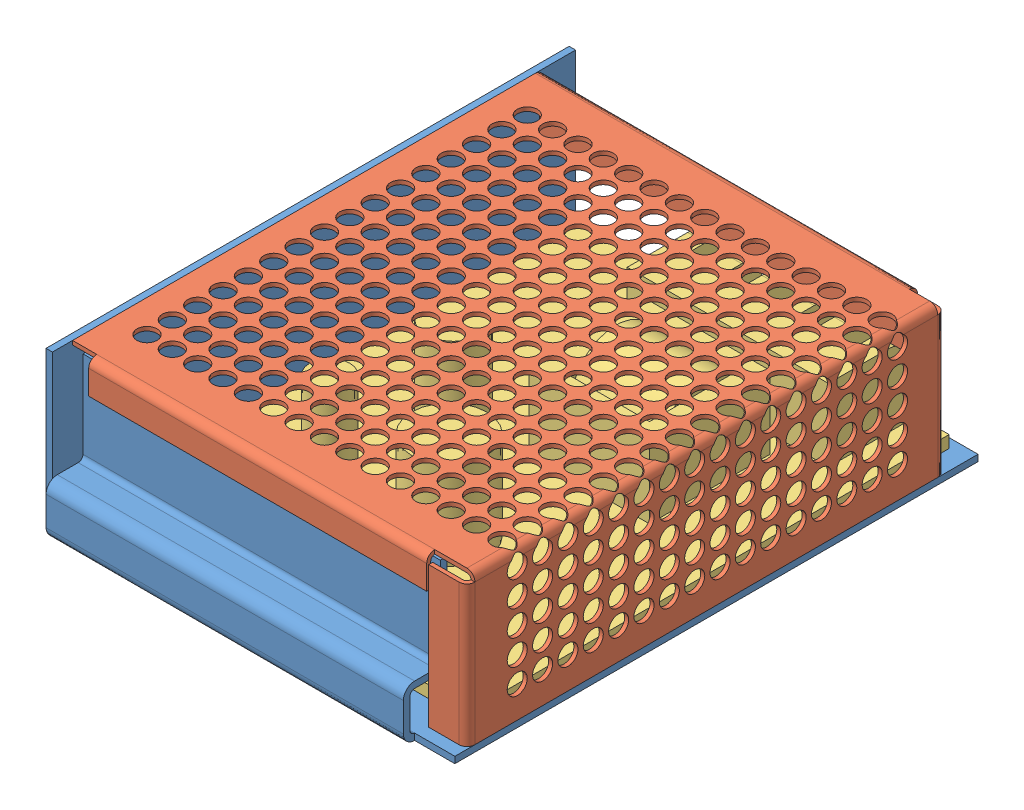
SolidWorks assembly SMPS-24v, configuration Default. Lengths in mm.
Overall size (101.6 38.6 132.8).
8 component instances, 4 part files, 0 mates.
Components (placement in the parent):
- Smps part 1-edit-00-1: Smps part 1-edit-00 [Default] at (3.0479 73.0195 107.4159) size (101.6 38.6 132.8)
- Smps part 2-edit-00-1: Smps part 2-edit-00 [Default] at (3.0479 73.0195 109.9159) size (100 37 119)
- part3-edit-00-1: part3-edit-00 [Default] at (3.0479 36.0195 107.4159) x (1 0 0) z (0 1 0) size (92.52 118.51 25)
- pan cross head_am_B18.6.7M - M5 x 0.8 x 10 Type I Cross Recessed PHMS --10N-1: pan cross head_am_B18.6.7M - M5 x 0.8 x 10 Type I Cross Recessed PHMS --10N [Default] at (83.1766 48.7195 51.7585) x (0 -1 0) z (0 0 1) size (13.86 9.5 9.57)
- pan cross head_am_B18.6.7M - M5 x 0.8 x 10 Type I Cross Recessed PHMS --10N-2: pan cross head_am_B18.6.7M - M5 x 0.8 x 10 Type I Cross Recessed PHMS --10N [Default] at (74.1766 48.7195 51.7585) x (0 -1 0) z (0 0 1) size (13.86 9.5 9.57)
- pan cross head_am_B18.6.7M - M5 x 0.8 x 10 Type I Cross Recessed PHMS --10N-3: pan cross head_am_B18.6.7M - M5 x 0.8 x 10 Type I Cross Recessed PHMS --10N [Default] at (65.1766 48.7195 51.7585) x (0 -1 0) z (0 0 1) size (13.86 9.5 9.57)
- pan cross head_am_B18.6.7M - M5 x 0.8 x 10 Type I Cross Recessed PHMS --10N-4: pan cross head_am_B18.6.7M - M5 x 0.8 x 10 Type I Cross Recessed PHMS --10N [Default] at (56.1766 48.7195 51.7585) x (0 -1 0) z (0 0 1) size (13.86 9.5 9.57)
- pan cross head_am_B18.6.7M - M5 x 0.8 x 10 Type I Cross Recessed PHMS --10N-5: pan cross head_am_B18.6.7M - M5 x 0.8 x 10 Type I Cross Recessed PHMS --10N [Default] at (47.1766 48.7195 51.7585) x (0 -1 0) z (0 0 1) size (13.86 9.5 9.57)
